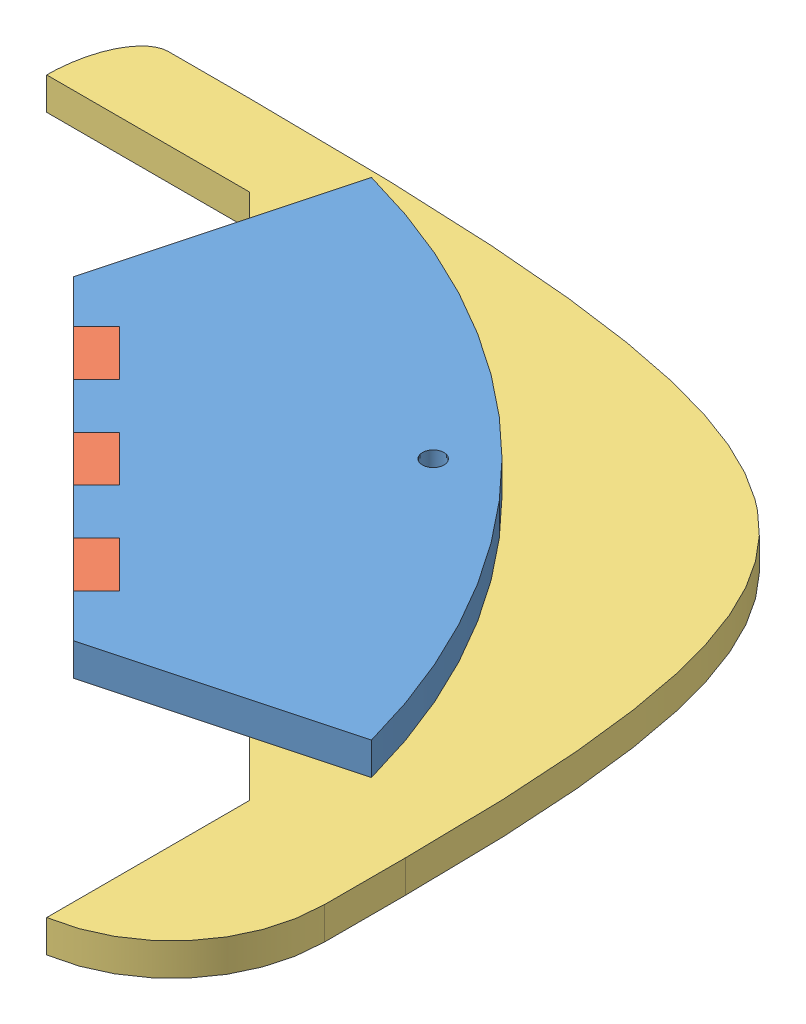
SolidWorks assembly bumper_total_RL, configuration MirrorDefault. Lengths in mm.
Overall size (134.33 15.24 127.03).
3 component instances, 3 part files, 6 mates.
Components (placement in the parent):
- bumper_top-1: bumper_top [MirrorDefault] at (-52.8514 69.6772 58.426) size (86.19 5.08 86.19)
- bumper_flange-1: bumper_flange [MirrorDefault] at (-24.4456 59.5172 -5.9008) x (0.707107 0 0.707107) z (-0.707107 0 0.707107) size (50.8 15.24 5.08)
- bumper_RL-2: bumper_RL [Default] at (-62.9783 64.5972 68.5529)
Mates (geometry in assembly coordinates):
- Width1: width: plane of bumper_top-1 through (-52.8514 74.7572 58.426) normal (-0.965926 0 -0.258819); plane of bumper_top-1 through (-52.8514 74.7572 58.426) normal (0.258819 0 0.965926); plane of bumper_flange-1 through (-28.0377 59.5172 -2.3087) normal (-0.707107 0 -0.707107); plane of bumper_flange-1 through (7.8833 59.5172 33.6123) normal (0.707107 0 0.707107)
- Coincident2: coincident: plane of bumper_top-1 through (-10.0772 74.7572 15.6518) normal (-0.707107 0 0.707107); plane of bumper_flange-1 through (-28.0377 59.5172 -2.3087) normal (-0.707107 0 0.707107)
- Coincident3: coincident: plane of bumper_top-1 through (-52.8514 74.7572 58.426) normal (0 1 0); plane of bumper_flange-1 through (-28.0377 74.7572 -2.3087) normal (0 1 0)
- Coincident4: coincident: plane of bumper_top-1 through (-52.8514 69.6772 58.426) normal (0 -1 0); plane of bumper_RL-2 through (-50.2783 69.6772 55.8529) normal (0 1 0)
- Concentric2: concentric: cylinder of bumper_top-1 through (18.0926 74.7572 -12.518) axis (0 1 0) radius 1.7; cylinder of bumper_RL-2 through (18.0926 69.6772 -12.518) axis (0 -1 0) radius 1.8
- Width2: width: plane of bumper_top-1 through (-52.8514 74.7572 58.426) normal (-0.965926 0 -0.258819); plane of bumper_top-1 through (-52.8514 74.7572 58.426) normal (0.258819 0 0.965926); plane of bumper_RL-2 through (44.9717 69.6772 43.1529) normal (-1 0 0); plane of bumper_RL-2 through (-62.9783 69.6772 -39.3971) normal (0 0 1)
